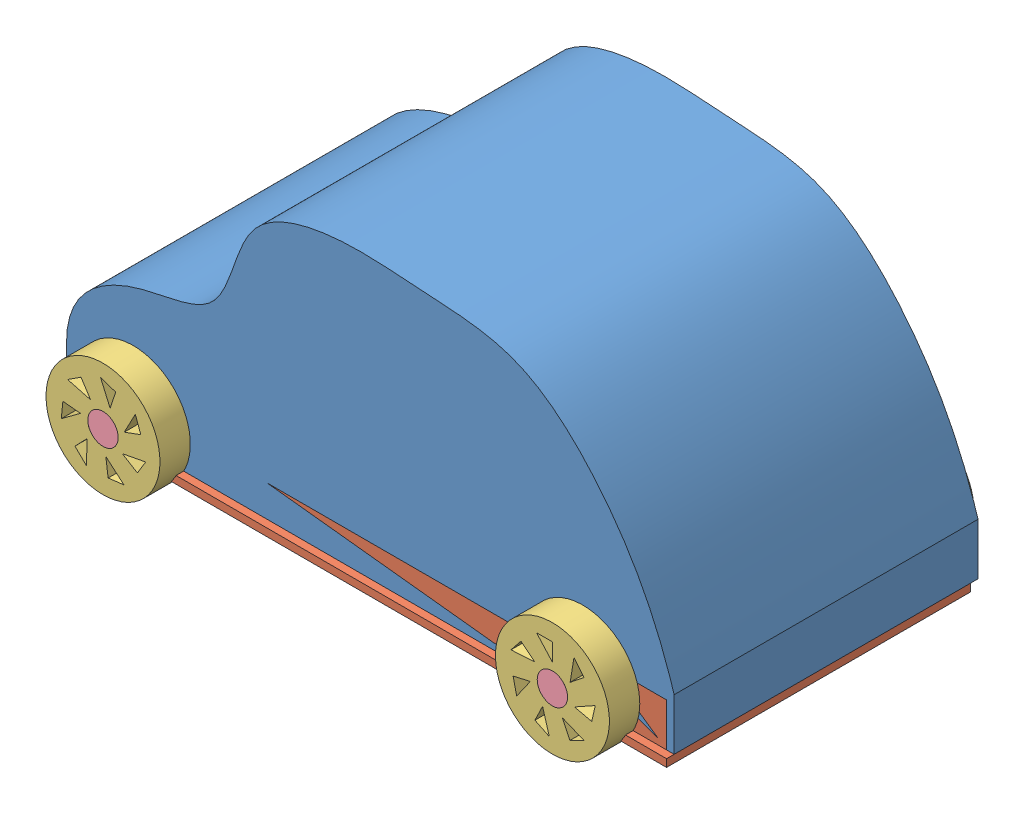
SolidWorks assembly robo7, configuration Default. Lengths in mm.
Overall size (214.46 115.94 121.92).
8 component instances, 4 part files, 12 mates.
Components (placement in the parent):
- s1-2: s1 [Default] at (81.5662 79.8893 113.575) size (214.46 97.89 101.6)
- f7-2: f7 [Default] at (108.2341 55.5259 141.7824) size (203.2 17.02 101.6)
- f77-3: f77 [Default] at (9.9078 94.7414 103.415) x (-0.588347 0.808609 0) z (0 0 1) size (38.1 38.1 10.16)
- f77-4: f77 [Default] at (5.1733 94.1769 215.175) x (-0.717867 0.696181 0) z (0 0 1) size (38.1 38.1 10.16)
- f77-5: f77 [Default] at (184.1101 51.3459 103.415) size (38.1 38.1 10.16)
- f77-6: f77 [Default] at (184.1101 51.3459 215.175) size (38.1 38.1 10.16)
- 777-2: 777 [Default] at (16.3133 61.2512 113.575) size (12.7 12.7 121.92)
- 777-3: 777 [Default] at (166.5993 61.2512 113.575) size (12.7 12.7 121.92)
Mates (geometry in assembly coordinates):
- Coincident4: coincident aligned: circle of s1-2; circle of 777-3
- Concentric2: concentric anti-aligned: cylinder of f77-5 through (161.1059 66.9559 113.575) axis (0 0 -1) radius 5.08; cylinder of 777-3 through (161.1059 66.9559 103.415) axis (0 0 1) radius 5.08
- Coincident5: coincident anti-aligned: circle of f77-5; circle of 777-3
- Concentric3: concentric aligned: cylinder of f77-6 through (161.1059 66.9559 225.335) axis (0 0 -1) radius 5.08; cylinder of 777-3 through (161.1059 66.9559 225.335) axis (0 0 -1) radius 5.08
- Coincident6: coincident aligned: circle of f77-6; circle of 777-3
- Coincident7: coincident anti-aligned: line of s1-2 through (-9.0069 58.0659 116.115) axis (1 0 0); line of f7-2 through (191.6531 58.0659 116.115) axis (-1 0 0)
- Coincident8: coincident anti-aligned: line of s1-2 through (-11.5469 58.0659 215.175) axis (0 0 -1); line of f7-2 through (-11.5469 58.0659 116.115) axis (0 0 1)
- Coincident9: coincident aligned: circle of s1-2; circle of 777-2
- Concentric4: concentric aligned: cylinder of f77-4 through (10.8199 66.9559 225.335) axis (0 0 -1) radius 5.08; cylinder of 777-2 through (10.8199 66.9559 225.335) axis (0 0 -1) radius 5.08
- Coincident10: coincident aligned: circle of f77-4; circle of 777-2
- Concentric5: concentric anti-aligned: cylinder of f77-3 through (10.8199 66.9559 113.575) axis (0 0 -1) radius 5.08; cylinder of 777-2 through (10.8199 66.9559 103.415) axis (0 0 1) radius 5.08
- Coincident11: coincident anti-aligned: circle of f77-3; circle of 777-2
